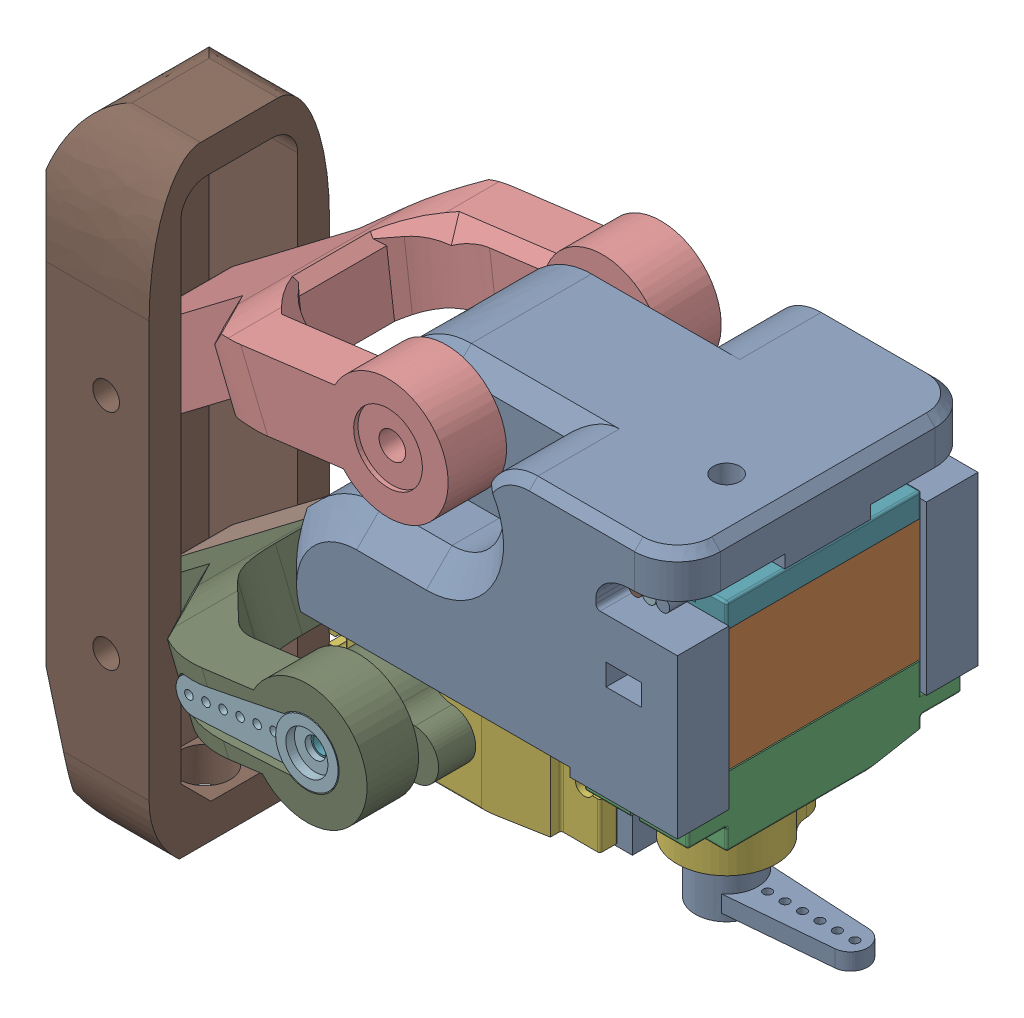
SolidWorks assembly leg assembly mirror, configuration Défaut. Lengths in mm.
Overall size (92.31 71.03 49).
9 component instances, 7 part files, 21 mates.
Components (placement in the parent):
- leg servos support mirror-1: leg servos support mirror [Défaut] at (46.2898 -19.6853 0) size (46.56 39.06 35.03)
- SERVO MG92B-1: SERVO MG92B [Predeterminado] at (-13.7052 -13.2153 -27.78) x (-1 0 0) z (0 1 0) size (31.69 33.93 12.06)
- SERVO MG92B-2: SERVO MG92B [Predeterminado] at (9.8198 12.3447 -17.5) x (0 0 1) z (1 0 0) size (31.69 33.93 12.06)
- bottom bar pin side mirror-1: bottom bar pin side mirror [Défaut] at (-19.0102 -13.2153 -42.855) x (-0.992008 -0.126175 0) z (0 0 -1) size (51 22.55 23.65)
- bottom bar servo side mirror-1: bottom bar servo side mirror [Défaut] at (-19.0102 -13.2153 -42.855) x (-0.992008 -0.126175 0) z (0 0 -1) size (51 22.55 25.35)
- Top bar leg-1: Top bar leg [Défaut] at (-19.0102 12.8147 -33.4) x (-0.992008 -0.126175 0) z (0 0 -1) size (51 22.55 32.54)
- leg end-1: leg end [Défaut] at (-52.2336 -49.7171 -7) x (-1 0 0) z (0 0 -1) size (14.15 71.11 21.11)
- servo horn single-1: servo horn single [Défaut] at (-19.0102 -13.2153 2.45) x (-0.992008 -0.126175 0) z (0 0 1) size (19.83 7.27 5.4)
- servo horn single-2: servo horn single [Défaut] at (9.8198 -17.8853 -12.195) x (0.99987 0 -0.016093) z (0 -1 0) size (19.83 7.27 5.4)
Mates (geometry in assembly coordinates):
- Parallèle1: parallel anti-aligned: plane of leg servos support mirror-1 through (-2.2102 -7.1853 -35) normal (0 -1 0); plane of SERVO MG92B-1 through (-2.3702 -7.1853 -2.63) normal (0 1 0)
- Coïncidente2: coincident anti-aligned: plane of leg servos support mirror-1 through (-13.7102 -19.6853 -7.25) normal (0 0 1); plane of SERVO MG92B-1 through (2.1398 -19.2453 -7.25) normal (0 0 -1)
- Coïncidente3: coincident anti-aligned: plane of leg servos support mirror-1 through (3.7898 -35.1853 -29) normal (1 0 0); plane of SERVO MG92B-2 through (3.7898 -12.8053 -28.835) normal (-1 0 0)
- Coïncidente4: coincident anti-aligned: plane of leg servos support mirror-1 through (-13.7102 -8.1853 0) normal (0 -1 0); plane of SERVO MG92B-2 through (15.8498 -8.1853 -1.655) normal (0 1 0)
- Largeur2: width anti-aligned: plane of leg servos support mirror-1 through (16.2898 -35.1853 -6) normal (0 0 -1); plane of SERVO MG92B-2 through (16.2898 -35.1853 -29) normal (0 0 1); plane of leg servos support mirror-1 through (3.7898 -12.8053 -6.165) normal (0 0 1); plane of SERVO MG92B-2 through (3.7898 -12.8053 -28.835) normal (0 0 -1)
- Coaxiale1: concentric anti-aligned: cylinder of leg servos support mirror-1 through (-19.0102 -13.2153 -27) axis (0 0 -1) radius 1.55; cylinder of bottom bar pin side mirror-1 through (-19.0102 -13.2153 -46.9533) axis (0 0 1) radius 1.55
- Coaxiale2: concentric aligned: cylinder of SERVO MG92B-1 through (-19.0102 -13.2153 3.27) axis (0 0 1) radius 1.925; cylinder of bottom bar servo side mirror-1 through (-19.0102 -13.2153 -2.155) axis (0 0 1) radius 3.75
- Coaxiale4: concentric anti-aligned: cylinder of leg servos support mirror-1 through (-19.0102 -13.2153 -27) axis (0 0 -1) radius 1.55; cylinder of SERVO MG92B-1 through (-19.0102 -13.2153 3.27) axis (0 0 1) radius 1.925
- Coïncidente7: coincident anti-aligned: plane of bottom bar pin side mirror-1 through (-19.0102 -13.2153 -17.505) normal (0 0 1); plane of bottom bar servo side mirror-1 through (-19.0102 -13.2153 -17.505) normal (0 0 -1)
- Largeur3: width anti-aligned: plane of bottom bar pin side mirror-1 through (-9.0168 -19.1564 -35.155) normal (0 0 1); plane of leg servos support mirror-1 through (-9.0168 -19.1564 1.845) normal (0 0 -1); plane of bottom bar servo side mirror-1 through (-13.7102 -19.6853 -35) normal (0 0 -1); plane of SERVO MG92B-1 through (-15.7437 -10.2969 1.69) normal (0 0 1)
- Coaxiale5: concentric anti-aligned: cylinder of leg servos support mirror-1 through (-19.0102 12.8147 -35) axis (0 0 1) radius 1.55; cylinder of Top bar leg-1 through (-19.0102 12.8147 -1.6) axis (0 0 -1) radius 1.55
- Largeur4: width anti-aligned: plane of Top bar leg-1 through (-16.1669 45.9381 -26.6) normal (0 0 1); plane of leg servos support mirror-1 through (-16.1669 45.9381 -8.4) normal (0 0 -1); plane of Top bar leg-1 through (-13.7102 -19.6853 -26.5) normal (0 0 -1); plane of leg servos support mirror-1 through (-13.7102 -19.6853 -8.5) normal (0 0 1)
- Coaxiale6: concentric aligned: cylinder of Top bar leg-1 through (-57.2336 -3.6871 -1.6) axis (0 0 -1) radius 1.55; cylinder of leg end-1 through (-57.2336 -3.6871 4.5) axis (0 0 -1) radius 1.55
- Coaxiale7: concentric aligned: cylinder of bottom bar servo side mirror-1 through (-57.2336 -29.7171 -17.505) axis (0 0 1) radius 1.55; cylinder of bottom bar pin side mirror-1 through (-57.2336 -29.7171 -41.155) axis (0 0 1) radius 1.55
- Largeur5: width anti-aligned: plane of Top bar leg-1 through (-19.0102 12.8147 -10.75) normal (0 0 1); plane of leg end-1 through (-19.0102 12.8147 -24.25) normal (0 0 -1); plane of Top bar leg-1 through (-52.2336 -49.7171 -10.7) normal (0 0 -1); plane of leg end-1 through (-52.2336 -49.7171 -24.3) normal (0 0 1)
- Coaxiale8: concentric anti-aligned: cylinder of SERVO MG92B-1 through (-19.0102 -13.2153 3.27) axis (0 0 1) radius 1.925; cylinder of servo horn single-1 through (-19.0102 -13.2153 6.15) axis (0 0 -1) radius 2.45
- Coaxiale10: concentric aligned: cylinder of bottom bar servo side mirror-1 through (-27.6407 -14.3131 -5.005) axis (0 0 1) radius 1.05; cylinder of servo horn single-1 through (-27.6407 -14.3131 3.3) axis (0 0 1) radius 0.5
- Coïncidente8: coincident anti-aligned: plane of SERVO MG92B-1 through (-19.0102 -13.2153 6.15) normal (0 0 1); plane of servo horn single-1 through (-19.0102 -13.2153 6.15) normal (0 0 -1)
- Coaxiale11: concentric anti-aligned: cylinder of SERVO MG92B-2 through (9.8198 -18.7053 -12.195) axis (0 -1 0) radius 1.925; cylinder of servo horn single-2 through (9.8198 -21.5853 -12.195) axis (0 1 0) radius 2.45
- Coïncidente9: coincident anti-aligned: plane of SERVO MG92B-2 through (9.8198 -21.5853 -12.195) normal (0 -1 0); plane of servo horn single-2 through (9.8198 -21.5853 -12.195) normal (0 1 0)
- Coaxiale14: concentric anti-aligned: cylinder of bottom bar servo side mirror-1 through (-57.2336 -29.7171 -17.505) axis (0 0 1) radius 1.55; cylinder of leg end-1 through (-57.2336 -29.7171 4.5) axis (0 0 -1) radius 1.55
